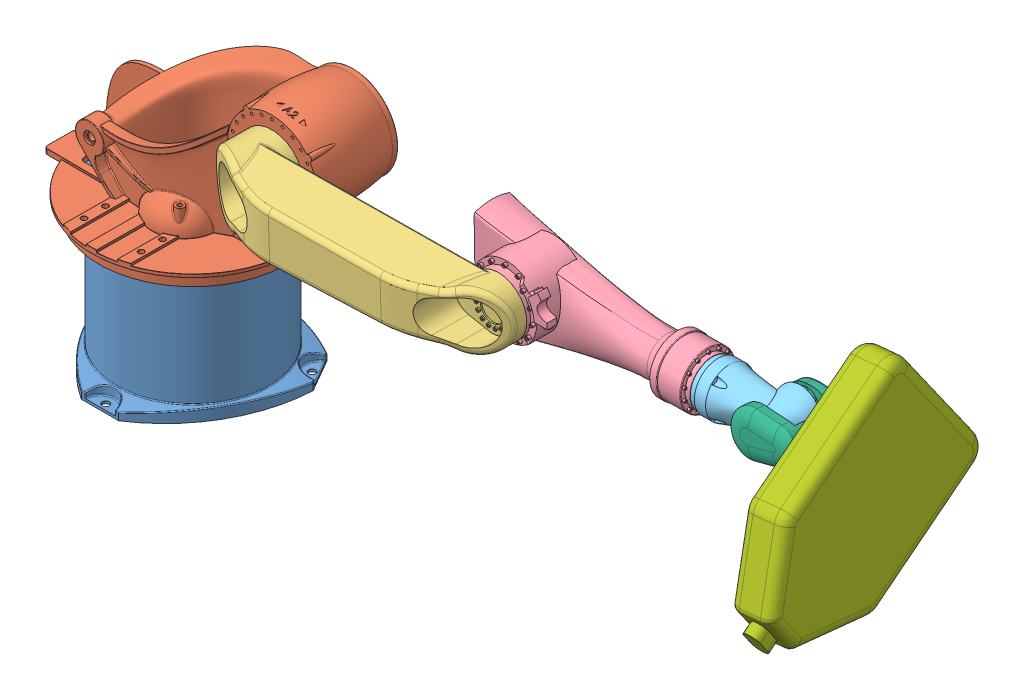
SolidWorks assembly ck_robot_assem_v2, configuration Default. Lengths in mm.
Overall size (2322.28 953.94 762.87).
7 component instances, 7 part files, 13 mates.
Components (placement in the parent):
- base_1-1: base_1 [Default] at (-3.833 13.0503 -2.7073) size (550.69 399.36 522.06)
- Body_1-1: Body_1 [Default] at (-57.0352 233.8026 27.5351) x (0.999982 0 0.006051) z (-0.006051 0 0.999982) size (746.32 414.53 595.61)
- lower_arm_1-1: lower_arm_1 [Default] at (280.5566 619.0503 99.0156) x (0.031831 -0.999493 0.000193) z (-0.006051 0 0.999982) size (187.33 850.33 185)
- upper_arm_1-1: upper_arm_1 [Default] at (1437.8052 626.1629 -26.9838) x (-0.999842 -0.016714 -0.006051) z (0.006051 0 -0.999982) size (623.51 292.37 209)
- wrist1-1: wrist1 [Default] at (1437.8052 626.1629 -26.9838) x (0.00748 -0.086864 -0.996192) z (0.016124 -0.99608 0.086975) size (135 253.96 135)
- wrist2-1: wrist2 [Default] at (1627.3862 633.8555 25.9677) x (0.00748 -0.086864 -0.996192) z (0.995545 0.094282 -0.000745) size (201.56 125.71 265.7)
- end_effector_v1-1: end_effector_v1 [Default] at (1827.0507 709.3893 -112.8704) x (0.077738 -0.825275 -0.559355) z (0.995545 0.094282 -0.000745) size (400 621.71 160)
Mates (geometry in assembly coordinates):
- Coincident1: coincident anti-aligned: plane of base_1-1 through (-3.833 376.0503 -2.7073) normal (0 1 0); plane of Body_1-1 through (252.0623 376.0503 -1.1587) normal (0 -1 0)
- Concentric1: concentric anti-aligned: cylinder of base_1-1 through (-3.833 345.0503 -2.7073) axis (0 1 0) radius 259.3432; cylinder of Body_1-1 through (-3.833 340.0503 -2.7073) axis (0 -1 0) radius 255.9
- Concentric2: concentric anti-aligned: circle of Body_1-1; circle of lower_arm_1-1
- Coincident2: coincident anti-aligned: plane of Body_1-1 through (406.7964 619.0503 59.7788) normal (-0.006051 0 0.999982); plane of lower_arm_1-1 through (437.6119 608.3837 59.9652) normal (0.006051 0 -0.999982)
- Coincident3: coincident anti-aligned: plane of lower_arm_1-1 through (960.2178 640.6957 100.1284) normal (0.006051 0 -0.999982); plane of upper_arm_1-1 through (960.2178 640.6957 100.1284) normal (-0.006051 0 0.999982)
- Coincident4: coincident aligned: circle of lower_arm_1-1; circle of upper_arm_1-1
- Coincident5: coincident anti-aligned: plane of upper_arm_1-1 through (1437.8052 626.1629 -26.9838) normal (0.999842 0.016714 0.006051); plane of wrist1-1 through (1437.8052 626.1629 -26.9838) normal (-0.999842 -0.016714 -0.006051)
- Concentric3: concentric aligned: cylinder of upper_arm_1-1 through (1307.8257 623.9902 -27.7704) axis (-0.999842 -0.016714 -0.006051) radius 64; cylinder of wrist1-1 through (1452.8028 626.4136 -26.8931) axis (-0.999842 -0.016714 -0.006051) radius 64
- Coincident6: coincident anti-aligned: plane of wrist1-1 through (1627.4086 633.5949 22.9792) normal (-0.00748 0.086864 0.996192); plane of wrist2-1 through (1627.4086 633.5949 22.9792) normal (0.00748 -0.086864 -0.996192)
- Coincident7: coincident anti-aligned: plane of wrist1-1 through (1628.239 623.953 -87.5982) normal (0.00748 -0.086864 -0.996192); plane of wrist2-1 through (1628.239 623.953 -87.5982) normal (-0.00748 0.086864 0.996192)
- Coincident8: coincident aligned: circle of wrist1-1; circle of wrist2-1
- Concentric4: concentric anti-aligned: cylinder of wrist2-1 through (1832.8351 649.0212 -22.9992) axis (-0.995545 -0.094282 0.000745) radius 44.45; cylinder of end_effector_v1-1 through (1793.0133 645.2499 -22.9694) axis (0.995545 0.094282 -0.000745) radius 37.5
- Coincident9: coincident aligned: circle of wrist2-1; circle of end_effector_v1-1
